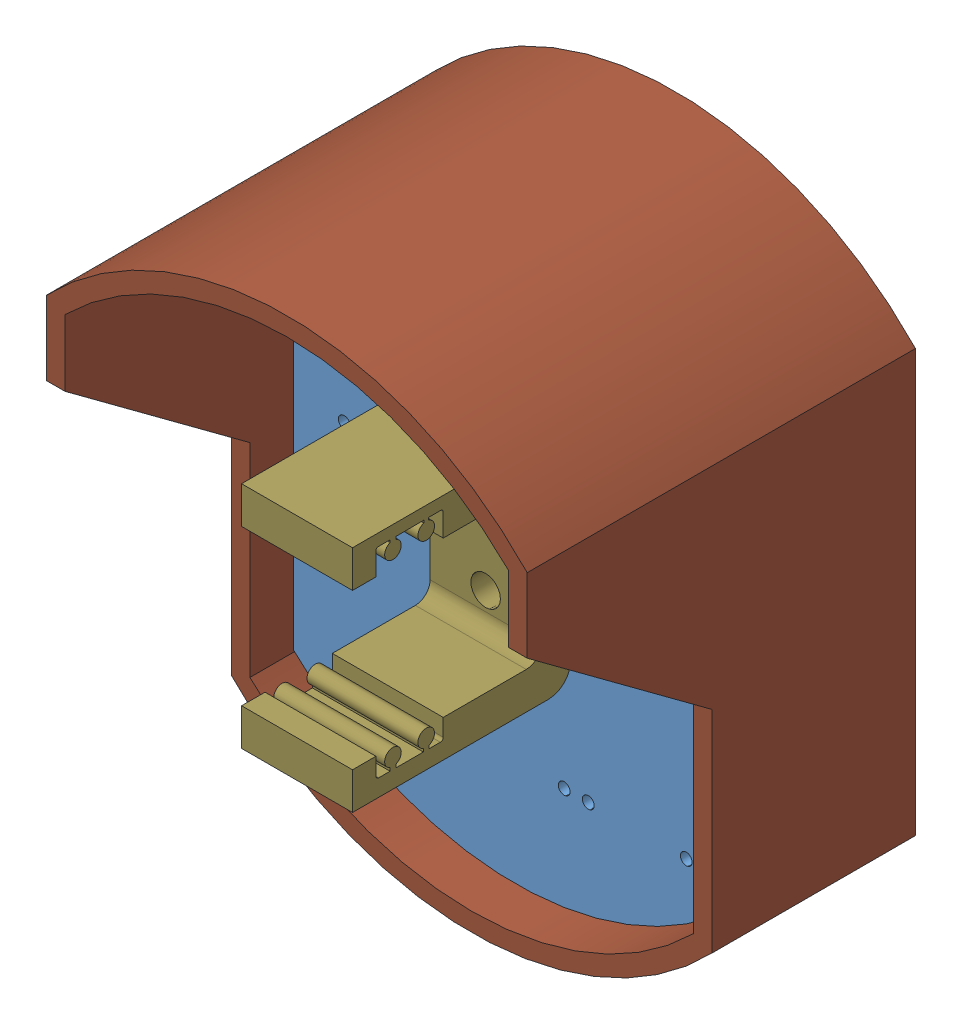
SolidWorks assembly Face_mount, configuration Valor predeterminado. Lengths in mm.
Overall size (130 169.58 105).
27 component instances, 12 part files, 22 mates.
Components (placement in the parent):
- Back_face-1: Back_face [Valor predeterminado] at origin size (120 155.57 8)
- PCB_LED_3-1: PCB_LED_3 [Valor predeterminado] at (60 -26.375 -1) x (0 1 0) z (0 0 1) size (50 98 1)
  - PCB_LED-1: PCB_LED [Valor predeterminado] at origin size (50 32 1)
  - PCB_LED-2: PCB_LED [Valor predeterminado] at (0 -33 0) size (50 32 1)
  - PCB_LED-3: PCB_LED [Valor predeterminado] at (0 33 0) size (50 32 1)
- PCB_LED_3-2: PCB_LED_3 [Valor predeterminado] at (60 -82.375 -1) x (0 1 0) z (0 0 1) size (50 98 1)
  - PCB_LED-1: PCB_LED [Valor predeterminado] at origin size (50 32 1)
  - PCB_LED-2: PCB_LED [Valor predeterminado] at (0 -33 0) size (50 32 1)
  - PCB_LED-3: PCB_LED [Valor predeterminado] at (0 33 0) size (50 32 1)
- Frontal_face-1: Frontal_face [Valor predeterminado] at (0 0 -30.25) size (120 158.33 38)
- LEDs_face_mount-1: LEDs_face_mount [Valor predeterminado] at (59.9 -54.275 -24.5) x (1 0 0) z (0 1 0) size (96 9.3 64)
  - LED_Matrix-1: LED_Matrix [Valor predeterminado] at (0 -1.5 -16) size (32 9.3 32)
  - LED_Matrix-2: LED_Matrix [Valor predeterminado] at (32 -1.5 -16) size (32 9.3 32)
  - LED_Matrix-3: LED_Matrix [Valor predeterminado] at (-32 -1.5 -16) size (32 9.3 32)
  - LED_Matrix-4: LED_Matrix [Valor predeterminado] at (-32 -1.5 16) size (32 9.3 32)
  - LED_Matrix-5: LED_Matrix [Valor predeterminado] at (32 -1.5 16) size (32 9.3 32)
  - LED_Matrix-6: LED_Matrix [Valor predeterminado] at (0 -1.5 16) size (32 9.3 32)
- RasPi_Camera-1: RasPi_Camera [FOV] at (60 2.8993 -27.8017) x (-1 0 0) z (0 -1 0) size (25 8.25 24)
  - RasPi_Camera_Board-1: RasPi_Camera_Board [Standard] at (0 -0.5517 0) x (-1 0 0) z (0 0 -1) size (25 3.5 24)
  - OVA5647-2: OVA5647 [FOV] at (0.0315 -0.3517 0.0586) size (8 5.3 16.75)
    - OVA5647-1: OVA5647 [Standard] at (0.32 0 -0.175) size (8 0.68 8)
    - OVA5647_Housing-1: OVA5647_Housing [Standard] at origin size (8 3.95 8)
    - OVA5647_IR-Glas-1: OVA5647_IR-Glas [Standard] at (0 0.95 0) x (-1 0 0) z (0 0 1) size (6.3 0.35 6.3)
    - OVA5647_Lens-1: OVA5647_Lens [FOV] at (0 3.95 0) size (6 3.35 6)
    - OVA5647_Pigtail-1: OVA5647_Pigtail [Standard] at origin size (8 1.3 16.75)
- Head_cover-1: Head_cover [Valor predeterminado] at (0 0.625 -30.25) size (130 169.58 105)
- Servo_support-1: Servo_support [Valor predeterminado] at (60 -48.875 8) size (30 62 59)
Mates (geometry in assembly coordinates):
- Coincidente5: coincident: plane of assembly; plane of assembly; plane of Back_face-1 through (60 -60.208 0) normal (0 0 -1); plane of PCB_LED_3-2/PCB_LED-1 through (60 -82.375 0) normal (0 0 1)
- Coincidente8: coordinate: point of assembly; point of Back_face-1; point of assembly
- Coincidente9: coincident: circle of assembly; circle of assembly; circle of Back_face-1; circle of PCB_LED_3-1/PCB_LED-1
- Coincidente12: coincident: circle of assembly; circle of assembly; circle of Back_face-1; circle of PCB_LED_3-2/PCB_LED-3
- Coincidente13: coincident: circle of assembly; circle of assembly; circle of Back_face-1; circle of PCB_LED_3-2/PCB_LED-2
- Paralelo5: parallel: line of assembly; line of assembly; line of Back_face-1 through (116.5738 115.8 -112.6619) axis (0 0 1); line of PCB_LED_3-1/PCB_LED-2 through (48 109 -50.375) axis (0 0 1)
- Coincidente17: coincident: line of assembly; line of assembly; line of Back_face-1 through (120 -108.75 5.75) axis (0 1 0); line of Frontal_face-1 through (120 -108.75 5.75) axis (0 1 0)
- Coincidente18: coincident: line of assembly; line of assembly; line of Back_face-1 through (0 -108.75 5.75) axis (0 1 0); line of Frontal_face-1 through (0 0 5.75) axis (0 -1 0)
- Coincidente19: coincident: point of assembly; point of assembly; point of Back_face-1; point of Frontal_face-1
- Distância4: distance = 0.1 mm: plane of assembly; plane of assembly; plane of LEDs_face_mount-1/LED_Matrix-6 through (43.9 -22.275 -24.5) normal (0 1 0); plane of Frontal_face-1 through (11.8 -22.175 -24.25) normal (0 -1 0)
- Distância5: distance = 0.1 mm: plane of assembly; plane of assembly; plane of LEDs_face_mount-1/LED_Matrix-4 through (11.9 -54.275 -24.5) normal (-1 0 0); plane of Frontal_face-1 through (11.8 -86.575 -24.25) normal (1 0 0)
- Coincidente31: coincident: plane of assembly; plane of assembly; plane of Frontal_face-1 through (60 -60.208 -30.25) normal (0 0 -1); plane of LEDs_face_mount-1/LED_Matrix-1 through (59.9 -70.275 -30.25) normal (0 0 -1)
- Coincidente32: coincident: plane of assembly; plane of assembly; plane of Frontal_face-1 through (0 0 -27.25) normal (0 0 1); plane of RasPi_Camera-1/RasPi_Camera_Board-1 through (60 2.8993 -27.25) normal (0 0 -1)
- Concêntrico1: concentric: circle of assembly; circle of assembly; circle of Frontal_face-1; circle of RasPi_Camera-1/RasPi_Camera_Board-1
- Concêntrico2: concentric: circle of assembly; circle of assembly; circle of Frontal_face-1; circle of RasPi_Camera-1/RasPi_Camera_Board-1
- Concêntrico3: concentric: circle of assembly; circle of assembly; circle of Frontal_face-1; circle of RasPi_Camera-1/RasPi_Camera_Board-1
- Coincidente33: coincident: plane of assembly; plane of assembly; plane of Frontal_face-1 through (0 0 -24.25) normal (-1 0 0); plane of Head_cover-1 through (0 0.625 69.75) normal (1 0 0)
- Coincidente35: coincident: plane of assembly; plane of assembly; plane of Frontal_face-1 through (60 -60.208 -30.25) normal (0 0 -1); plane of Head_cover-1 through (60 -59.583 -30.25) normal (0 0 1)
- Distância6: distance = 0.625 mm: point of assembly; line of assembly; point of Back_face-1; line of Head_cover-1 through (0 0.625 69.75) axis (0 0 -1)
- Coincidente36: coincident: plane of assembly; plane of assembly; plane of Back_face-1 through (60 -60.208 8) normal (0 0 1); plane of Servo_support-1 through (60 -48.875 8) normal (0 0 -1)
- Concêntrico4: concentric: cylinder of assembly; cylinder of assembly; cylinder of Back_face-1 through (60 -36.875 2.4) axis (0 0 1) radius 4; cylinder of Servo_support-1 through (60 -36.875 67) axis (0 0 -1) radius 4
- Concêntrico5: concentric: cylinder of assembly; cylinder of assembly; cylinder of Back_face-1 through (60 -60.875 2.4) axis (0 0 1) radius 4; cylinder of Servo_support-1 through (60 -60.875 67) axis (0 0 -1) radius 4
